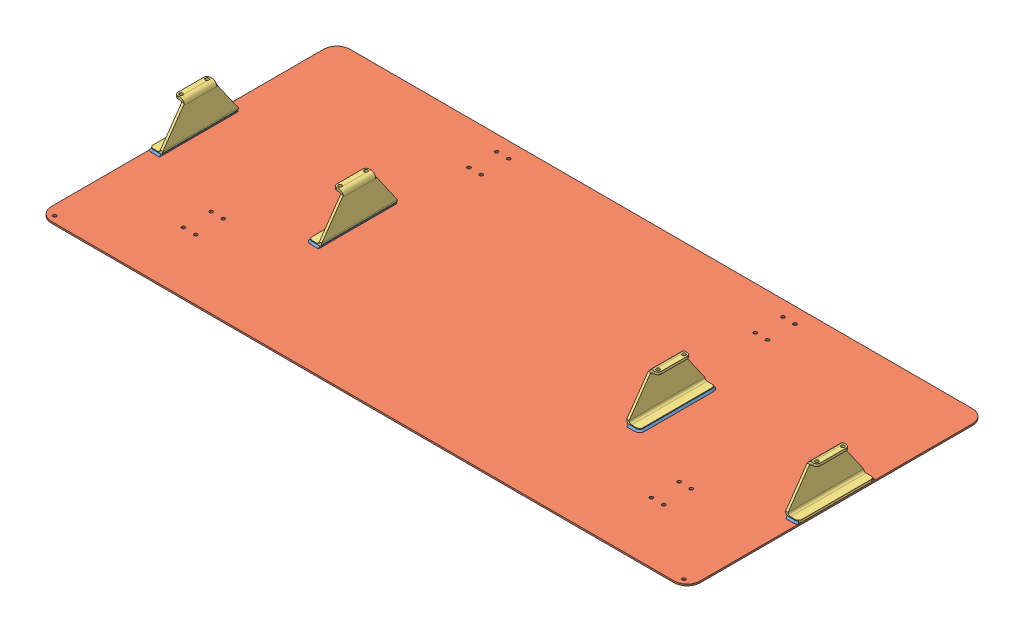
SolidWorks assembly GE-16177_ASM, configuration Default. Lengths in mm.
Overall size (1270.03 79.38 584.2).
6 component instances, 3 part files, 0 mates.
Components (placement in the parent):
- GE-16177_ASM-1: GE-16177_ASM [Default] at origin size (1270.03 3.22 154.35)
- GE-16016-1: GE-16016 [Default] at origin size (1270 3.17 584.2)
- GE-16177-01-1: GE-16177-01 [Default] at (-614.3625 3.175 0) size (25.4 76.2 147.96)
- GE-16177-01-2: GE-16177-01 [Default] at (614.3625 3.175 0) x (-1 0 0) z (0 0 -1) size (25.4 76.2 147.96)
- GE-16177-01-3: GE-16177-01 [Default] at (303.2125 3.175 0) x (-1 0 0) z (0 0 -1) size (25.4 76.2 147.96)
- GE-16177-01-4: GE-16177-01 [Default] at (-303.2125 3.175 0) size (25.4 76.2 147.96)
